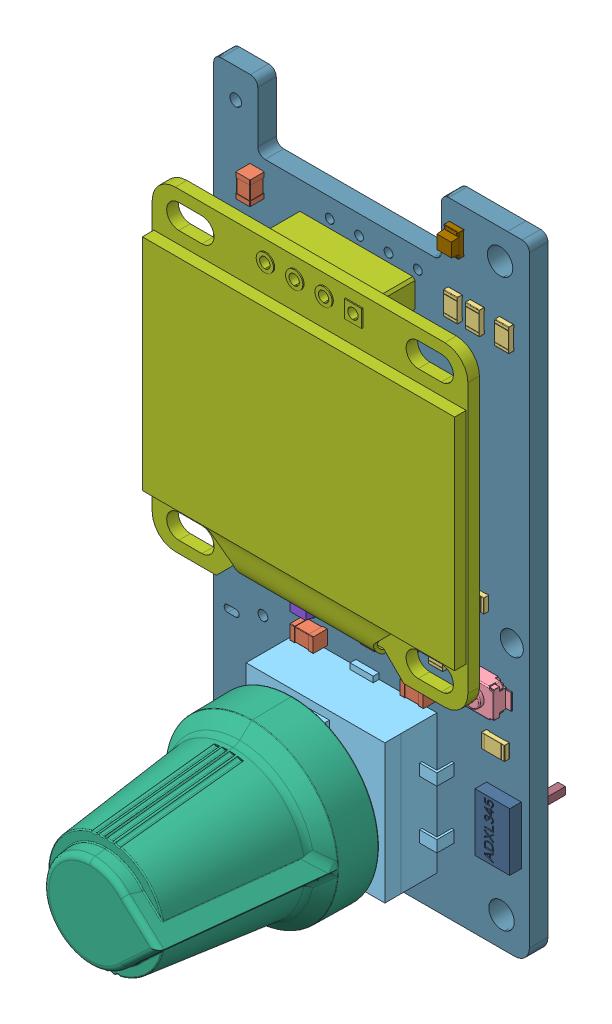
SolidWorks assembly rak4260_complet, configuration Défaut. Lengths in mm.
Overall size (27.53 54.61 35.01).
70 component instances, 14 part files, 0 mates.
Components (placement in the parent):
- rak4260_complet.step-1: rak4260_complet.step [Défaut] at origin size (27.53 54.61 35.01)
  - 4260.step-1: 4260.step [Défaut] at (104.14 -63.5 1.65) size (15 15 1.4)
    - SOLID.step-1: SOLID.step [Défaut] at origin size (15 15 1.4)
  - C_0805_2012Metric.step-1: C_0805_2012Metric.step [Défaut] at (105.41 -44.45 1.65) x (0 -1 0) z (0 0 1) size (2 1.25 1.25)
    - SOLID-0.step-1: SOLID-0.step [Défaut] at origin size (2 1.25 1.25)
  - R_0805_2012Metric.step-1: R_0805_2012Metric.step [Défaut] at (118.11 -67.945 1.65) size (2 1.2 0.45)
    - SOLID-1.step-1: SOLID-1.step [Défaut] at origin size (2 1.2 0.45)
  - R_0805_2012Metric.step-2: R_0805_2012Metric.step [Défaut] at (113.665 -67.945 1.65) x (-1 0 0) z (0 0 1) size (2 1.2 0.45)
    - SOLID-1.step-1: SOLID-1.step [Défaut] at origin size (2 1.2 0.45)
  - R_0805_2012Metric.step-3: R_0805_2012Metric.step [Défaut] at (109.5525 -67.945 1.65) x (-1 0 0) z (0 0 1) size (2 1.2 0.45)
    - SOLID-1.step-1: SOLID-1.step [Défaut] at origin size (2 1.2 0.45)
  - SW_SPST_B3U-1000P.step-1: SW_SPST_B3U-1000P.step [Défaut] at (125.476 -72.39 1.65) size (4 2.51 1.59)
    - SOLID-2.step-1: SOLID-2.step [Défaut] at origin size (4 2.51 1.59)
  - encoder-EC11.step-1: encoder-EC11.step [Défaut] at (114.95 -82.51 1.65) x (1 0 0) z (0 -1 0) size (15 20.5 13)
    - SOLID-3.step-1: SOLID-3.step [Défaut] at origin size (15 20.5 13)
  - VCKnob.step-1: VCKnob.step [Défaut] at (114.95 -82.51 8.15) x (1 0 0) z (0 -1 0) size (15 17.51 15)
    - SOLID-4.step-1: SOLID-4.step [Défaut] at origin size (15 17.51 15)
  - C_0805_2012Metric.step-2: C_0805_2012Metric.step [Défaut] at (123.19 -67.945 1.65) size (2 1.25 1.25)
    - SOLID-0.step-1: SOLID-0.step [Défaut] at origin size (2 1.25 1.25)
  - OLED_27x27.step-1: OLED_27x27.step [Défaut] at (115.481 -56.596 6.15) x (1 0 0) z (0 -1 0) size (27.3 5.03 27.3)
    - SOLID-5.step-1: SOLID-5.step [Défaut] at origin size (27.3 5.03 27.3)
  - C_0805_2012Metric.step-3: C_0805_2012Metric.step [Défaut] at (110.49 -75.565 1.65) x (-1 0 0) z (0 0 1) size (2 1.25 1.25)
    - SOLID-0.step-1: SOLID-0.step [Défaut] at origin size (2 1.25 1.25)
  - C_0805_2012Metric.step-4: C_0805_2012Metric.step [Défaut] at (107.95 -88.265 1.65) x (0 -1 0) z (0 0 1) size (2 1.25 1.25)
    - SOLID-0.step-1: SOLID-0.step [Défaut] at origin size (2 1.25 1.25)
  - C_0805_2012Metric.step-5: C_0805_2012Metric.step [Défaut] at (113.665 -71.755 1.65) x (0 1 0) z (0 0 1) size (2 1.25 1.25)
    - SOLID-0.step-1: SOLID-0.step [Défaut] at origin size (2 1.25 1.25)
  - C_0805_2012Metric.step-6: C_0805_2012Metric.step [Défaut] at (116.205 -72.39 1.65) x (0 1 0) z (0 0 1) size (2 1.25 1.25)
    - SOLID-0.step-1: SOLID-0.step [Défaut] at origin size (2 1.25 1.25)
  - C_0805_2012Metric.step-7: C_0805_2012Metric.step [Défaut] at (120.015 -74.93 1.65) size (2 1.25 1.25)
    - SOLID-0.step-1: SOLID-0.step [Défaut] at origin size (2 1.25 1.25)
  - C_0805_2012Metric.step-8: C_0805_2012Metric.step [Défaut] at (120.65 -63.5 1.65) x (0 1 0) z (0 0 1) size (2 1.25 1.25)
    - SOLID-0.step-1: SOLID-0.step [Défaut] at origin size (2 1.25 1.25)
  - R_0805_2012Metric.step-4: R_0805_2012Metric.step [Défaut] at (126.238 -76.2 1.65) x (-1 0 0) z (0 0 1) size (2 1.2 0.45)
    - SOLID-1.step-1: SOLID-1.step [Défaut] at origin size (2 1.2 0.45)
  - R_0805_2012Metric.step-5: R_0805_2012Metric.step [Défaut] at (103.505 -64.77 1.65) x (0 1 0) z (0 0 1) size (2 1.2 0.45)
    - SOLID-1.step-1: SOLID-1.step [Défaut] at origin size (2 1.2 0.45)
  - R_0805_2012Metric.step-6: R_0805_2012Metric.step [Défaut] at (123.825 -52.07 1.65) x (0 1 0) z (0 0 1) size (2 1.2 0.45)
    - SOLID-1.step-1: SOLID-1.step [Défaut] at origin size (2 1.2 0.45)
  - R_0805_2012Metric.step-7: R_0805_2012Metric.step [Défaut] at (122.555 -45.085 1.65) x (0 1 0) z (0 0 1) size (2 1.2 0.45)
    - SOLID-1.step-1: SOLID-1.step [Défaut] at origin size (2 1.2 0.45)
  - R_0805_2012Metric.step-8: R_0805_2012Metric.step [Défaut] at (121.285 -71.755 1.65) x (0 1 0) z (0 0 1) size (2 1.2 0.45)
    - SOLID-1.step-1: SOLID-1.step [Défaut] at origin size (2 1.2 0.45)
  - R_0805_2012Metric.step-9: R_0805_2012Metric.step [Défaut] at (124.46 -45.085 1.65) x (0 1 0) z (0 0 1) size (2 1.2 0.45)
    - SOLID-1.step-1: SOLID-1.step [Défaut] at origin size (2 1.2 0.45)
  - R_0805_2012Metric.step-10: R_0805_2012Metric.step [Défaut] at (124.46 -66.04 1.65) size (2 1.2 0.45)
    - SOLID-1.step-1: SOLID-1.step [Défaut] at origin size (2 1.2 0.45)
  - R_0805_2012Metric.step-11: R_0805_2012Metric.step [Défaut] at (127 -45.085 1.65) x (0 1 0) z (0 0 1) size (2 1.2 0.45)
    - SOLID-1.step-1: SOLID-1.step [Défaut] at origin size (2 1.2 0.45)
  - SOT-23-5.step-1: SOT-23-5.step [Défaut] at (110.49 -72.39 1.65) size (2.8 2.9 1.55)
    - SOLID-6.step-1: SOLID-6.step [Défaut] at origin size (2.8 2.9 1.55)
  - LED_0805_2012Metric.step-1: LED_0805_2012Metric.step [Défaut] at (118.745 -71.755 1.65) x (0 -1 0) z (0 0 1) size (2 1.25 1.1)
    - SOLID-7.step-1: SOLID-7.step [Défaut] at origin size (2 1.25 1.1)
  - LED_0805_2012Metric.step-2: LED_0805_2012Metric.step [Défaut] at (122.682 -40.132 1.65) x (0 1 0) z (0 0 1) size (2 1.25 1.1)
    - SOLID-7.step-1: SOLID-7.step [Défaut] at origin size (2 1.25 1.1)
  - ADXL345.step-1: ADXL345.step [Défaut] at (125.246 -84.542 1.65) size (3 5 1)
    - SOLID-8.step-1: SOLID-8.step [Défaut] at origin size (3 5 1)
  - SOT-23.step-1: SOT-23.step [Défaut] at (114.808 -58.166 -0.05) x (0 1 0) z (0 0 -1) size (2.5 3 1.2)
    - SOLID-9.step-1: SOLID-9.step [Défaut] at origin size (2.5 3 1.2)
  - R_0805_2012Metric.step-12: R_0805_2012Metric.step [Défaut] at (114.808 -60.96 -0.05) x (1 0 0) z (0 0 -1) size (2 1.2 0.45)
    - SOLID-1.step-1: SOLID-1.step [Défaut] at origin size (2 1.2 0.45)
  - R_0805_2012Metric.step-13: R_0805_2012Metric.step [Défaut] at (125.984 -77.724 -0.05) x (-1 0 0) z (0 0 -1) size (2 1.2 0.45)
    - SOLID-1.step-1: SOLID-1.step [Défaut] at origin size (2 1.2 0.45)
  - R_0805_2012Metric.step-14: R_0805_2012Metric.step [Défaut] at (125.984 -75.184 -0.05) x (1 0 0) z (0 0 -1) size (2 1.2 0.45)
    - SOLID-1.step-1: SOLID-1.step [Défaut] at origin size (2 1.2 0.45)
  - D_0805_2012Metric.step-1: D_0805_2012Metric.step [Défaut] at (114.799 -54.102 -0.05) x (1 0 0) z (0 0 -1) size (2 1.27 0.8)
    - SOLID-10.step-1: SOLID-10.step [Défaut] at origin size (2 1.27 0.8)
  - PinHeader_1x05_P2.54mm_Vertical_SMD_Pin1Right.step-1: PinHeader_1x05_P2.54mm_Vertical_SMD_Pin1Right.step [Défaut] at (115.824 -87.63 -0.05) x (0 -1 0) z (0 0 -1) size (5 12.7 9.3)
    - SOLID-11.step-1: SOLID-11.step [Défaut] at origin size (5 12.7 9.3)
  - COMPOUND.step-1: COMPOUND.step [Défaut] at origin size (27.3 54.61 1.6)
